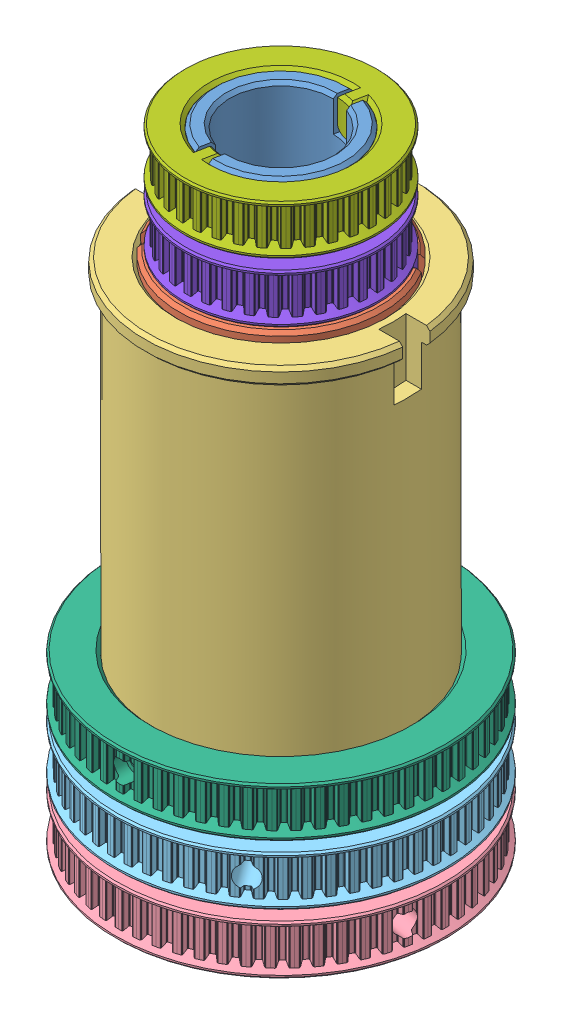
SolidWorks assembly tubes assembly v5, configuration Default. Lengths in mm.
Overall size (136.32 196.5 136.32).
8 component instances, 8 part files, 23 mates.
Components (placement in the parent):
- inner tube v5-1: inner tube v5 [Default] at (0 33.25 0) x (-0.191791 0 0.981436) z (-0.981436 0 -0.191791) size (50 196.5 50)
- middle tube v5-1: middle tube v5 [Default] at (0 59.25 0) x (0.805314 0 -0.592849) z (0.592849 0 0.805314) size (60 134 60)
- outer tube v5-1: outer tube v5 [Default] at origin size (79.6 114.5 80)
- big inner tube pulley v5-1: big inner tube pulley v5 [Default] at (0 -85 0) x (0 -1 0) z (-0.191791 0 0.981436) size (14.5 97.5 97.5)
- big middle tube pulley v5-1: big middle tube pulley v5 [Default] at (0 -67.5 0) x (0 -1 0) z (0.805314 0 -0.592849) size (14.5 97.5 97.5)
- big outer tube pulley v5-1: big outer tube pulley v5 [Default] at (0 -50 0) x (0 -1 0) z (-1 0 0) size (14.5 97.5 97.5)
- small inner tube pulley v5-1: small inner tube pulley v5 [Default] at (0 84 0) x (0 1 0) z (0.981436 0 0.191791) size (14.5 57 57)
- small middle tube pulley v5-1: small middle tube pulley v5 [Default] at (0 66.5 0) x (0 1 0) z (0.805314 0 -0.592849) size (34.5 57 57)
Mates (geometry in assembly coordinates):
- Coincident28: coordinate: point of outer tube v5-1
- Coincident8: coincident: plane of assembly through (0 0 0) normal (0 0 1); plane of assembly; plane of inner tube v5-1 through (0 33.25 0) normal (0 0 -1)
- Coincident9: coincident: plane of assembly through (0 0 0) normal (0 0 1); plane of assembly; plane of middle tube v5-1 through (0 59.25 0) normal (0 0 1)
- Coincident10: coincident: plane of assembly through (0 0 0) normal (0 0 1); plane of assembly; plane of outer tube v5-1
- Concentric1: concentric aligned: cylinder of middle tube v5-1 through (0 59.25 0) axis (0 -1 0) radius 30; cylinder of outer tube v5-1 through (0 57.25 0) axis (0 -1 0) radius 37.5
- Concentric2: concentric aligned: cylinder of inner tube v5-1 through (0 33.25 0) axis (0 -1 0) radius 25; cylinder of middle tube v5-1 through (0 59.25 0) axis (0 -1 0) radius 30
- Concentric6: concentric anti-aligned: cylinder of inner tube v5-1 through (0 33.25 0) axis (0 -1 0) radius 20; cylinder of small inner tube pulley v5-1 through (0 76.75 0) axis (0 1 0) radius 20
- Concentric7: concentric anti-aligned: cylinder of middle tube v5-1 through (0 59.25 0) axis (0 -1 0) radius 25; cylinder of small middle tube pulley v5-1 through (0 39.25 0) axis (0 1 0) radius 25
- Coincident12: coincident anti-aligned: plane of middle tube v5-1 through (0 59.25 0) normal (0 1 0); plane of small middle tube pulley v5-1 through (0 59.25 0) normal (0 -1 0)
- Distance5: distance = 3 mm anti-aligned: plane of small inner tube pulley v5-1 through (0 76.75 0) normal (0 -1 0); plane of small middle tube pulley v5-1 through (0 73.75 0) normal (0 1 0)
- Coincident17: coincident aligned: plane of inner tube v5-1 through (-3.8358 91.25 19.6287) normal (0 1 0); plane of small inner tube pulley v5-1 through (0 91.25 0) normal (0 1 0)
- Distance8: distance = 2 mm aligned: plane of outer tube v5-1 through (0 57.25 0) normal (0 1 0); plane of middle tube v5-1 through (0 59.25 0) normal (0 1 0)
- Coincident18: coincident anti-aligned: plane of inner tube v5-1 through (2.8207 81.25 -27.469) normal (0.981436 0 0.191791); plane of small inner tube pulley v5-1 through (-2.4536 81.25 -0.4795) normal (-0.981436 0 -0.191791)
- Coincident19: coincident anti-aligned: plane of middle tube v5-1 through (-26.7039 49.25 22.763) normal (-0.592849 0 -0.805314); plane of small middle tube pulley v5-1 through (1.4821 49.25 2.0133) normal (0.592849 0 0.805314)
- Concentric8: concentric aligned: cylinder of outer tube v5-1 through (0 57.25 0) axis (0 -1 0) radius 37.5; cylinder of big outer tube pulley v5-1 through (0 -42.75 0) axis (0 -1 0) radius 37.5
- Coincident21: coincident aligned: plane of outer tube v5-1 through (0 -57.25 0) normal (0 -1 0); plane of big outer tube pulley v5-1 through (0 -57.25 0) normal (0 -1 0)
- Coincident22: coincident anti-aligned: plane of outer tube v5-1 through (-45 -47.25 -2.5) normal (0 0 1); plane of big outer tube pulley v5-1 through (0 -47.25 -2.5) normal (0 0 -1)
- Concentric9: concentric aligned: cylinder of middle tube v5-1 through (0 59.25 0) axis (0 -1 0) radius 30; cylinder of big middle tube pulley v5-1 through (0 -60.25 0) axis (0 -1 0) radius 30
- Coincident23: coincident aligned: plane of middle tube v5-1 through (0 -74.75 0) normal (0 -1 0); plane of big middle tube pulley v5-1 through (0 -74.75 0) normal (0 -1 0)
- Concentric10: concentric aligned: cylinder of inner tube v5-1 through (0 33.25 0) axis (0 -1 0) radius 25; cylinder of big inner tube pulley v5-1 through (0 -77.75 0) axis (0 -1 0) radius 25
- Coincident25: coincident anti-aligned: plane of inner tube v5-1 through (9.1663 -82.25 -33.8708) normal (-0.981436 0 -0.191791); plane of big inner tube pulley v5-1 through (2.4536 -82.25 0.4795) normal (0.981436 0 0.191791)
- Distance9: distance = 13 mm aligned: plane of big inner tube pulley v5-1 through (0 -92.25 0) normal (0 -1 0); plane of inner tube v5-1 through (-3.8358 -105.25 19.6287) normal (0 -1 0)
- Coincident26: coincident anti-aligned: plane of middle tube v5-1 through (-26.7039 -64.75 22.763) normal (-0.592849 0 -0.805314); plane of big middle tube pulley v5-1 through (1.4821 -64.75 2.0133) normal (0.592849 0 0.805314)
